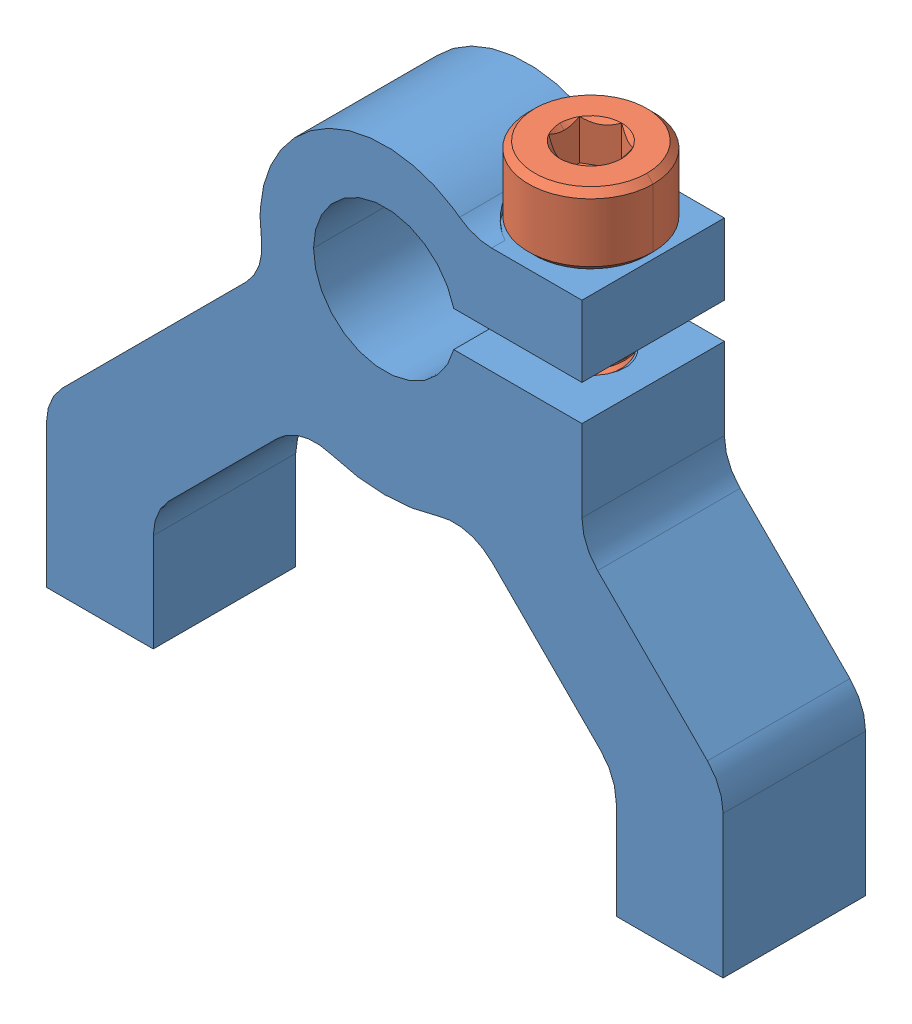
SolidWorks assembly 1-Side, 2-Post Clamping Mount (8mm Bore)1400-0032-0008, configuration Default. Lengths in mm.
Overall size (38 33.01 8).
2 component instances, 2 part files, 0 mates.
Components (placement in the parent):
- 1400-0032-0008.STEP-1: 1400-0032-0008.STEP [Default] at (-18.3987 7.1938 6.6805) size (38 31 8)
- 2800-0004-0010_90128A207.STEP-1: 2800-0004-0010_90128A207.STEP [Default] at (-10.8258 2.1938 10.6805) x (1 0 0) z (0 -1 0) size (7 7 14.01)
